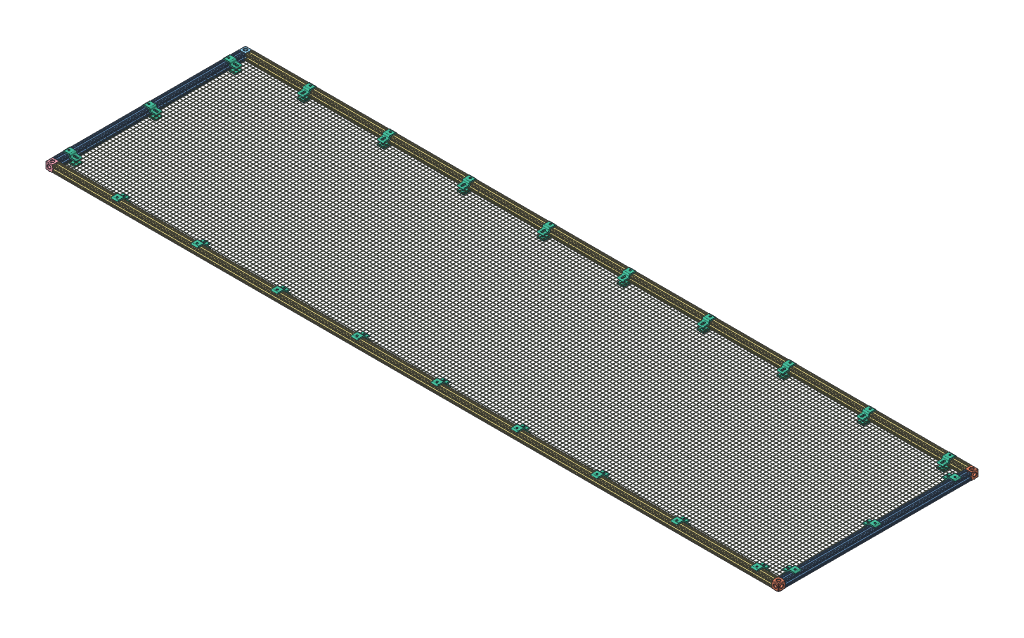
SolidWorks assembly north_face, configuration Default. Lengths in mm.
Overall size (2793.8 32.58 761.8).
33 component instances, 7 part files, 18 mates.
Components (placement in the parent):
- 47065T801_T-SLOTTED FRAMING_28inch-1: 47065T801_T-SLOTTED FRAMING_28inch [47065T801] at (335.2641 472.3491 708.3611) size (25.4 25.4 711.2)
- 47065T244_ALUMINUM T-SLOTTED FRAMING EXTRUSION-1: 47065T244_ALUMINUM T-SLOTTED FRAMING EXTRUSION [47065T244] at (322.6641 459.7491 1063.9611) size (27.7 27.7 27.7)
- 47065T801_T-SLOTTED FRAMING_108inch-1: 47065T801_T-SLOTTED FRAMING_108inch [47065T801] at (-1048.9359 472.3491 1076.5611) x (0 0 -1) z (1 0 0) size (25.4 25.4 2743.2)
- 47065T244_ALUMINUM T-SLOTTED FRAMING EXTRUSION-2: 47065T244_ALUMINUM T-SLOTTED FRAMING EXTRUSION [47065T244] at (322.6641 459.7491 352.7611) x (1 0 0) z (0 1 0) size (27.7 27.7 27.7)
- Mirror47065T244_ALUMINUM T-SLOTTED FRAMING EXTRUSION-4: Mirror47065T244_ALUMINUM T-SLOTTED FRAMING EXTRUSION [47065T244] at (-2420.5359 459.7491 1063.9611) x (-1 0 0) z (0 0 -1) size (27.7 27.7 27.7)
- 47065T801_T-SLOTTED FRAMING_28inch-3: 47065T801_T-SLOTTED FRAMING_28inch [47065T801] at (-2433.1359 472.3491 708.3611) x (-1 0 0) z (0 0 -1) size (25.4 25.4 711.2)
- 47065T801_T-SLOTTED FRAMING_108inch-2: 47065T801_T-SLOTTED FRAMING_108inch [47065T801] at (-1048.9359 472.3491 340.1611) x (0 0 1) z (-1 0 0) size (25.4 25.4 2743.2)
- MirrorMirror47065T244_ALUMINUM T-SLOTTED FRAMING EXTRUSION-5: MirrorMirror47065T244_ALUMINUM T-SLOTTED FRAMING EXTRUSION [47065T244] at (-2420.5359 459.7491 352.7611) x (-1 0 0) z (0 0 -1) size (27.7 27.7 27.7)
- 47065T197_ALUMINUM T-SLOTTED FRAMING EXTRUSION-2: 47065T197_ALUMINUM T-SLOTTED FRAMING EXTRUSION [47065T197] at (252.8141 485.0491 340.1611) x (-1 0 0) z (0 1 0) size (25.4 49.23 32.06)
- 05_wire_mesh_28x108-1: 05_wire_mesh_28x108 [47065T287] at (-2421.1566 472.3491 353.9692) x (1 0 0) z (0 -1 0) size (2743.72 711.2 2.08)
- 47065T197_ALUMINUM T-SLOTTED FRAMING EXTRUSION-3: 47065T197_ALUMINUM T-SLOTTED FRAMING EXTRUSION [47065T197] at (-51.9859 485.0491 340.1611) x (-1 0 0) z (0 1 0) size (25.4 49.23 32.06)
- 47065T197_ALUMINUM T-SLOTTED FRAMING EXTRUSION-4: 47065T197_ALUMINUM T-SLOTTED FRAMING EXTRUSION [47065T197] at (-356.7859 485.0491 340.1611) x (-1 0 0) z (0 1 0) size (25.4 49.23 32.06)
- 47065T197_ALUMINUM T-SLOTTED FRAMING EXTRUSION-5: 47065T197_ALUMINUM T-SLOTTED FRAMING EXTRUSION [47065T197] at (-661.5859 485.0491 340.1611) x (-1 0 0) z (0 1 0) size (25.4 49.23 32.06)
- 47065T197_ALUMINUM T-SLOTTED FRAMING EXTRUSION-6: 47065T197_ALUMINUM T-SLOTTED FRAMING EXTRUSION [47065T197] at (-966.3859 485.0491 340.1611) x (-1 0 0) z (0 1 0) size (25.4 49.23 32.06)
- 47065T197_ALUMINUM T-SLOTTED FRAMING EXTRUSION-7: 47065T197_ALUMINUM T-SLOTTED FRAMING EXTRUSION [47065T197] at (-1271.1859 485.0491 340.1611) x (-1 0 0) z (0 1 0) size (25.4 49.23 32.06)
- 47065T197_ALUMINUM T-SLOTTED FRAMING EXTRUSION-8: 47065T197_ALUMINUM T-SLOTTED FRAMING EXTRUSION [47065T197] at (-1575.9859 485.0491 340.1611) x (-1 0 0) z (0 1 0) size (25.4 49.23 32.06)
- 47065T197_ALUMINUM T-SLOTTED FRAMING EXTRUSION-9: 47065T197_ALUMINUM T-SLOTTED FRAMING EXTRUSION [47065T197] at (-1880.7859 485.0491 340.1611) x (-1 0 0) z (0 1 0) size (25.4 49.23 32.06)
- 47065T197_ALUMINUM T-SLOTTED FRAMING EXTRUSION-10: 47065T197_ALUMINUM T-SLOTTED FRAMING EXTRUSION [47065T197] at (-2185.5859 485.0491 340.1611) x (-1 0 0) z (0 1 0) size (25.4 49.23 32.06)
- 47065T197_ALUMINUM T-SLOTTED FRAMING EXTRUSION-11: 47065T197_ALUMINUM T-SLOTTED FRAMING EXTRUSION [47065T197] at (-51.9859 485.0491 1076.5611) x (1 0 0) z (0 1 0) size (25.4 49.23 32.06)
- 47065T197_ALUMINUM T-SLOTTED FRAMING EXTRUSION-12: 47065T197_ALUMINUM T-SLOTTED FRAMING EXTRUSION [47065T197] at (-356.7859 485.0491 1076.5611) x (1 0 0) z (0 1 0) size (25.4 49.23 32.06)
- 47065T197_ALUMINUM T-SLOTTED FRAMING EXTRUSION-13: 47065T197_ALUMINUM T-SLOTTED FRAMING EXTRUSION [47065T197] at (-661.5859 485.0491 1076.5611) x (1 0 0) z (0 1 0) size (25.4 49.23 32.06)
- 47065T197_ALUMINUM T-SLOTTED FRAMING EXTRUSION-14: 47065T197_ALUMINUM T-SLOTTED FRAMING EXTRUSION [47065T197] at (-966.3859 485.0491 1076.5611) x (1 0 0) z (0 1 0) size (25.4 49.23 32.06)
- 47065T197_ALUMINUM T-SLOTTED FRAMING EXTRUSION-15: 47065T197_ALUMINUM T-SLOTTED FRAMING EXTRUSION [47065T197] at (-1271.1859 485.0491 1076.5611) x (1 0 0) z (0 1 0) size (25.4 49.23 32.06)
- 47065T197_ALUMINUM T-SLOTTED FRAMING EXTRUSION-16: 47065T197_ALUMINUM T-SLOTTED FRAMING EXTRUSION [47065T197] at (-1575.9859 485.0491 1076.5611) x (1 0 0) z (0 1 0) size (25.4 49.23 32.06)
- 47065T197_ALUMINUM T-SLOTTED FRAMING EXTRUSION-17: 47065T197_ALUMINUM T-SLOTTED FRAMING EXTRUSION [47065T197] at (-1880.7859 485.0491 1076.5611) x (1 0 0) z (0 1 0) size (25.4 49.23 32.06)
- 47065T197_ALUMINUM T-SLOTTED FRAMING EXTRUSION-18: 47065T197_ALUMINUM T-SLOTTED FRAMING EXTRUSION [47065T197] at (-2185.5859 485.0491 1076.5611) x (1 0 0) z (0 1 0) size (25.4 49.23 32.06)
- 47065T197_ALUMINUM T-SLOTTED FRAMING EXTRUSION-19: 47065T197_ALUMINUM T-SLOTTED FRAMING EXTRUSION [47065T197] at (252.8141 485.0491 1076.5611) x (1 0 0) z (0 1 0) size (25.4 49.23 32.06)
- 47065T197_ALUMINUM T-SLOTTED FRAMING EXTRUSION-20: 47065T197_ALUMINUM T-SLOTTED FRAMING EXTRUSION [47065T197] at (-2433.1359 485.0491 1013.1611) x (0 0 1) z (0 1 0) size (25.4 49.23 32.06)
- 47065T197_ALUMINUM T-SLOTTED FRAMING EXTRUSION-21: 47065T197_ALUMINUM T-SLOTTED FRAMING EXTRUSION [47065T197] at (-2433.1359 485.0491 403.5611) x (0 0 1) z (0 1 0) size (25.4 49.23 32.06)
- 47065T197_ALUMINUM T-SLOTTED FRAMING EXTRUSION-22: 47065T197_ALUMINUM T-SLOTTED FRAMING EXTRUSION [47065T197] at (-2433.1359 485.0491 708.3611) x (0 0 1) z (0 1 0) size (25.4 49.23 32.06)
- 47065T197_ALUMINUM T-SLOTTED FRAMING EXTRUSION-23: 47065T197_ALUMINUM T-SLOTTED FRAMING EXTRUSION [47065T197] at (335.2641 485.0491 403.5611) x (0 0 -1) z (0 1 0) size (25.4 49.23 32.06)
- 47065T197_ALUMINUM T-SLOTTED FRAMING EXTRUSION-24: 47065T197_ALUMINUM T-SLOTTED FRAMING EXTRUSION [47065T197] at (335.2641 485.0491 708.3611) x (0 0 -1) z (0 1 0) size (25.4 49.23 32.06)
- 47065T197_ALUMINUM T-SLOTTED FRAMING EXTRUSION-25: 47065T197_ALUMINUM T-SLOTTED FRAMING EXTRUSION [47065T197] at (335.2641 485.0491 1013.1611) x (0 0 -1) z (0 1 0) size (25.4 49.23 32.06)
Mates (geometry in assembly coordinates):
- Concentric1: concentric anti-aligned: cylinder of 47065T801_T-SLOTTED FRAMING_28inch-1 through (335.2641 472.3491 352.7611) axis (0 0 1) radius 2.6035; cylinder of 47065T244_ALUMINUM T-SLOTTED FRAMING EXTRUSION-1 through (335.2641 472.3491 1063.9611) axis (0 0 -1) radius 3.6
- Coincident1: coincident anti-aligned: plane of 47065T801_T-SLOTTED FRAMING_28inch-1 through (335.2641 472.3491 1063.9611) normal (0 0 1); plane of 47065T244_ALUMINUM T-SLOTTED FRAMING EXTRUSION-1 through (322.6641 484.9491 1063.9611) normal (0 0 -1)
- Concentric2: concentric aligned: circle of 47065T244_ALUMINUM T-SLOTTED FRAMING EXTRUSION-1; circle of 47065T801_T-SLOTTED FRAMING_108inch-1
- Parallel1: parallel aligned: plane of 47065T244_ALUMINUM T-SLOTTED FRAMING EXTRUSION-1 through (322.6641 459.7491 1089.1611) normal (0 -1 0); plane of 47065T801_T-SLOTTED FRAMING_108inch-1 through (322.6641 459.6491 1063.8611) normal (0 -1 0)
- Coincident3: coincident anti-aligned: plane of 47065T244_ALUMINUM T-SLOTTED FRAMING EXTRUSION-1 through (322.6641 484.9491 1063.9611) normal (-1 0 0); plane of 47065T801_T-SLOTTED FRAMING_108inch-1 through (322.6641 472.3491 1076.5611) normal (1 0 0)
- Parallel2: parallel aligned: plane of 47065T801_T-SLOTTED FRAMING_28inch-1 through (347.9641 459.6491 1063.9611) normal (0 -1 0); plane of 47065T244_ALUMINUM T-SLOTTED FRAMING EXTRUSION-1 through (322.6641 459.7491 1089.1611) normal (0 -1 0)
- Concentric4: concentric anti-aligned: circle of 47065T801_T-SLOTTED FRAMING_28inch-1; circle of 47065T244_ALUMINUM T-SLOTTED FRAMING EXTRUSION-2
- Parallel3: parallel aligned: plane of 47065T801_T-SLOTTED FRAMING_28inch-1 through (347.9641 459.6491 1063.9611) normal (1 0 0); plane of 47065T244_ALUMINUM T-SLOTTED FRAMING EXTRUSION-2 through (347.8641 459.7491 327.5611) normal (1 0 0)
- Coincident6: coincident anti-aligned: plane of 47065T801_T-SLOTTED FRAMING_28inch-1 through (335.2641 472.3491 352.7611) normal (0 0 -1); plane of 47065T244_ALUMINUM T-SLOTTED FRAMING EXTRUSION-2 through (322.6641 484.9491 352.7611) normal (0 0 1)
- Coincident7: coincident: line of 47065T801_T-SLOTTED FRAMING_108inch-2 through (322.6641 485.0491 346.5047) axis (-1 0 0); plane of 47065T197_ALUMINUM T-SLOTTED FRAMING EXTRUSION-2 through (240.1141 485.0491 329.0359) normal (0 -1 0)
- Coincident8: coincident anti-aligned: plane of 47065T801_T-SLOTTED FRAMING_108inch-2 through (-2420.5359 459.6491 352.8611) normal (0 0 1); plane of 47065T197_ALUMINUM T-SLOTTED FRAMING EXTRUSION-2 through (240.1141 482.6615 352.8611) normal (0 0 -1)
- Coincident9: coincident anti-aligned: plane of 47065T801_T-SLOTTED FRAMING_28inch-1 through (335.2641 472.3491 708.3611) normal (0 1 0); plane of 05_wire_mesh_28x108-1 through (-2421.1566 472.3491 353.9692) normal (0 -1 0)
- Tangent1: tangent anti-aligned: plane of 47065T801_T-SLOTTED FRAMING_28inch-1 through (322.5641 459.6491 1063.9611) normal (-1 0 0); cylinder of 05_wire_mesh_28x108-1 through (322.0434 472.8693 1065.1692) axis (0 0 -1) radius 0.5207
- Distance1: distance = 12.7 mm anti-aligned: plane of 47065T801_T-SLOTTED FRAMING_108inch-1 through (-2420.5359 472.3491 1072.0399) normal (0 0 -1); cylinder of 05_wire_mesh_28x108-1 through (322.0434 471.8289 1058.8192) axis (-1 0 0) radius 0.5207
- Distance2: distance = 57.15 mm: plane of 47065T197_ALUMINUM T-SLOTTED FRAMING EXTRUSION-2 through (265.5141 485.0491 333.8111) normal (1 0 0); line of 47065T801_T-SLOTTED FRAMING_108inch-2 through (322.6641 485.0491 333.8174) axis (0 0 -1)
- Coincident14: coincident anti-aligned: plane of 47065T801_T-SLOTTED FRAMING_28inch-3 through (-2420.4359 459.6491 352.7611) normal (1 0 0); plane of 47065T197_ALUMINUM T-SLOTTED FRAMING EXTRUSION-20 through (-2420.4359 482.6615 1025.8611) normal (-1 0 0)
- Coincident17: coincident anti-aligned: plane of 47065T801_T-SLOTTED FRAMING_28inch-3 through (-2445.8359 485.0491 352.7611) normal (0 1 0); plane of 47065T197_ALUMINUM T-SLOTTED FRAMING EXTRUSION-20 through (-2444.2611 485.0491 1025.8611) normal (0 -1 0)
- Distance3: distance = 38.1 mm: plane of 47065T197_ALUMINUM T-SLOTTED FRAMING EXTRUSION-20 through (-2439.4859 485.0491 1025.8611) normal (0 0 1); line of 47065T801_T-SLOTTED FRAMING_28inch-3 through (-2442.7434 485.0491 1063.9611) axis (1 0 0)
